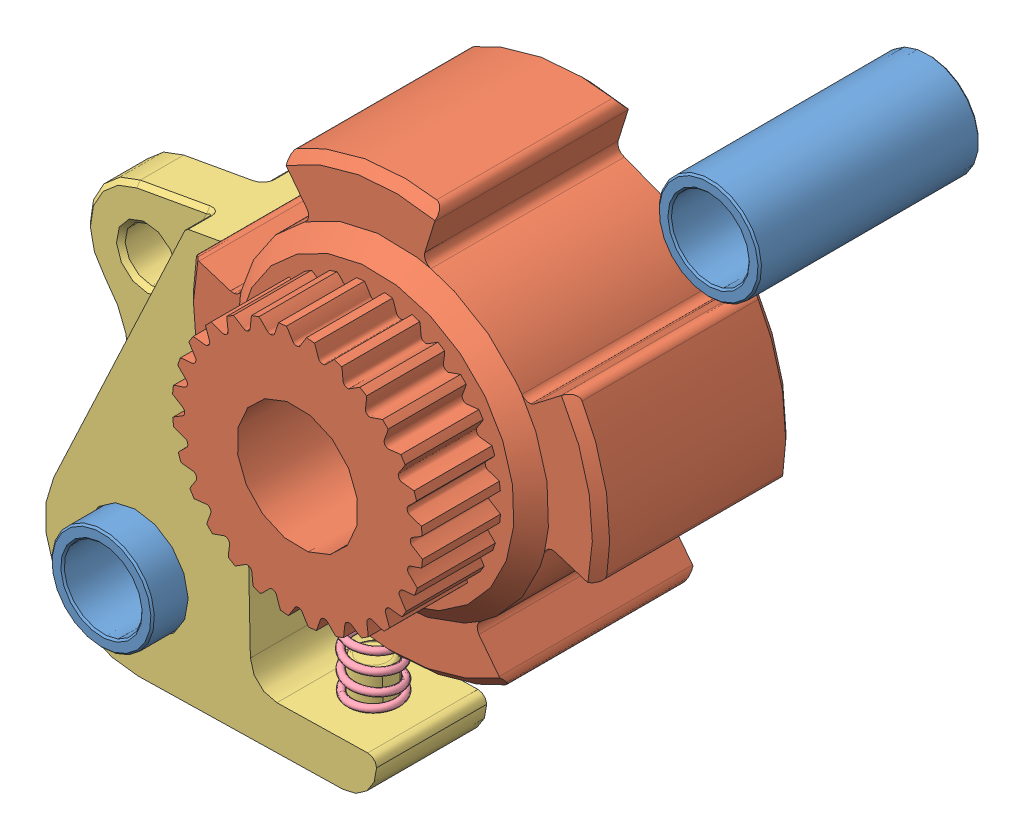
SolidWorks assembly 40-151 Ratchet, configuration Default. Lengths in mm.
Overall size (44.32 44.03 18.9).
7 component instances, 6 part files, 0 mates.
Components (placement in the parent):
- 217-6048-010 Rev10-1: 217-6048-010 Rev10 [Default] at origin (suppressed, hidden)
- 217-6048-011 Rev9-1: 217-6048-011 Rev9 [Default] at (0 0 0.3) (suppressed, hidden)
- 217-4783-006 Rev3-1: 217-4783-006 Rev3 [Default] at (17.5 17.5 0) x (-0.958378 0.285501 0) z (0 0 1) size (5.9 5.9 12.7)
- 217-6048-001 Rev19-1: 217-6048-001 Rev19 [Default] at (0 0 1.2) x (0.976671 -0.214742 0) z (0 0 1) size (23.97 23.97 16.71)
- 217-4783-006 Rev3-2: 217-4783-006 Rev3 [Default] at (-17.5 -17.5 0) x (0.923728 0.383049 0) z (0 0 1) size (5.9 5.9 12.7)
- 217-6048-003 Rev23-1: 217-6048-003 Rev23 [Default] at (-0.3723 0.3646 1.175) x (0.021054 -0.999778 0) z (0 0 -1) size (24.39 19.04 6.35)
- 217-6048-009 Rev4-1: 217-6048-009 Rev4 [Default] at (-6.9856 -19.5741 1.175) x (0.865211 0.01822 0.501076) z (-0.500965 -0.010549 0.865403) size (3.06 5.52 3.07)
